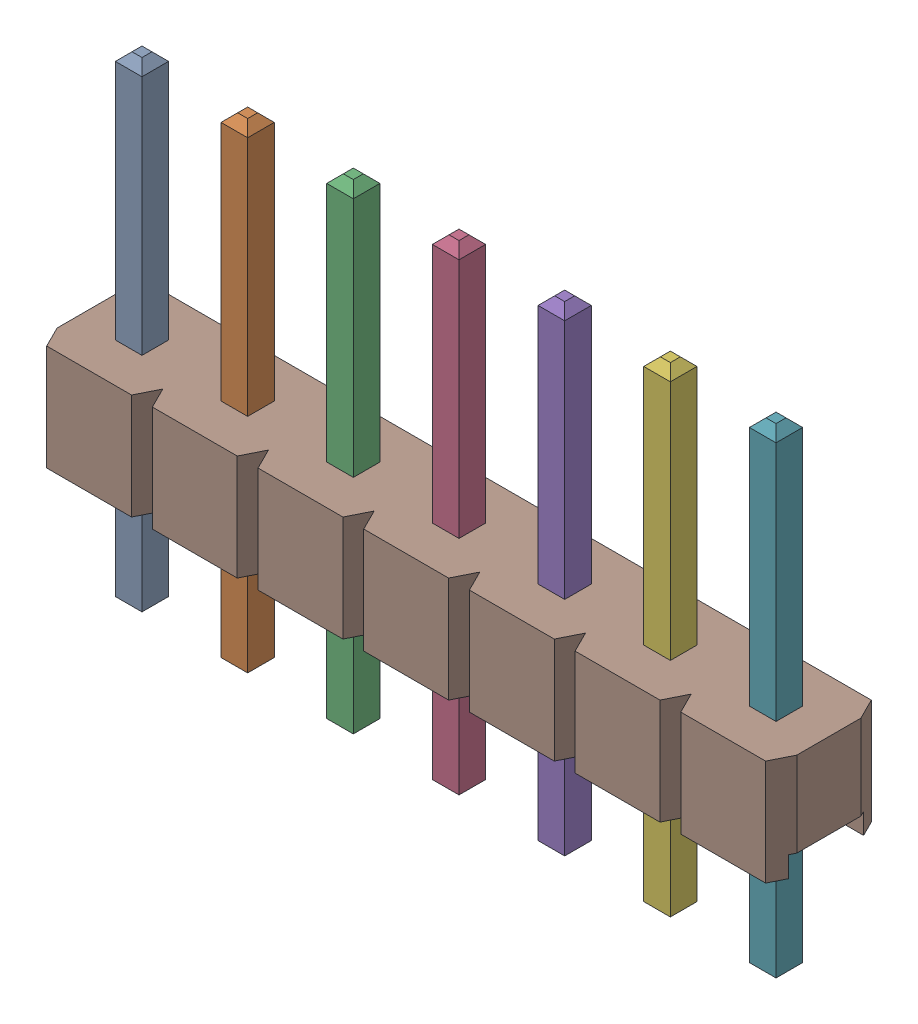
SolidWorks assembly STEP-7pin-61300711121-rev1, configuration Default. Lengths in mm.
Overall size (17.78 11.54 2.54).
8 component instances, 2 part files, 0 mates.
Components (placement in the parent):
- 6130xx11121_PIN-1: 6130xx11121_PIN [Default] at (-7.62 1.5 0) x (1 0 0) z (0 -1 0) size (0.64 0.64 11.54)
- 6130xx11121_PIN-2: 6130xx11121_PIN [Default] at (-5.08 1.5 0) x (1 0 0) z (0 -1 0) size (0.64 0.64 11.54)
- 6130xx11121_PIN-3: 6130xx11121_PIN [Default] at (-2.54 1.5 0) x (1 0 0) z (0 -1 0) size (0.64 0.64 11.54)
- 6130xx11121_PIN-4: 6130xx11121_PIN [Default] at (0 1.5 0) x (1 0 0) z (0 -1 0) size (0.64 0.64 11.54)
- 6130xx11121_PIN-5: 6130xx11121_PIN [Default] at (2.54 1.5 0) x (1 0 0) z (0 -1 0) size (0.64 0.64 11.54)
- 6130xx11121_PIN-6: 6130xx11121_PIN [Default] at (5.08 1.5 0) x (1 0 0) z (0 -1 0) size (0.64 0.64 11.54)
- 6130xx11121_PIN-7: 6130xx11121_PIN [Default] at (7.62 1.5 0) x (1 0 0) z (0 -1 0) size (0.64 0.64 11.54)
- 61300711121-1: 61300711121 [Default] at origin size (17.78 2.54 2.54)
